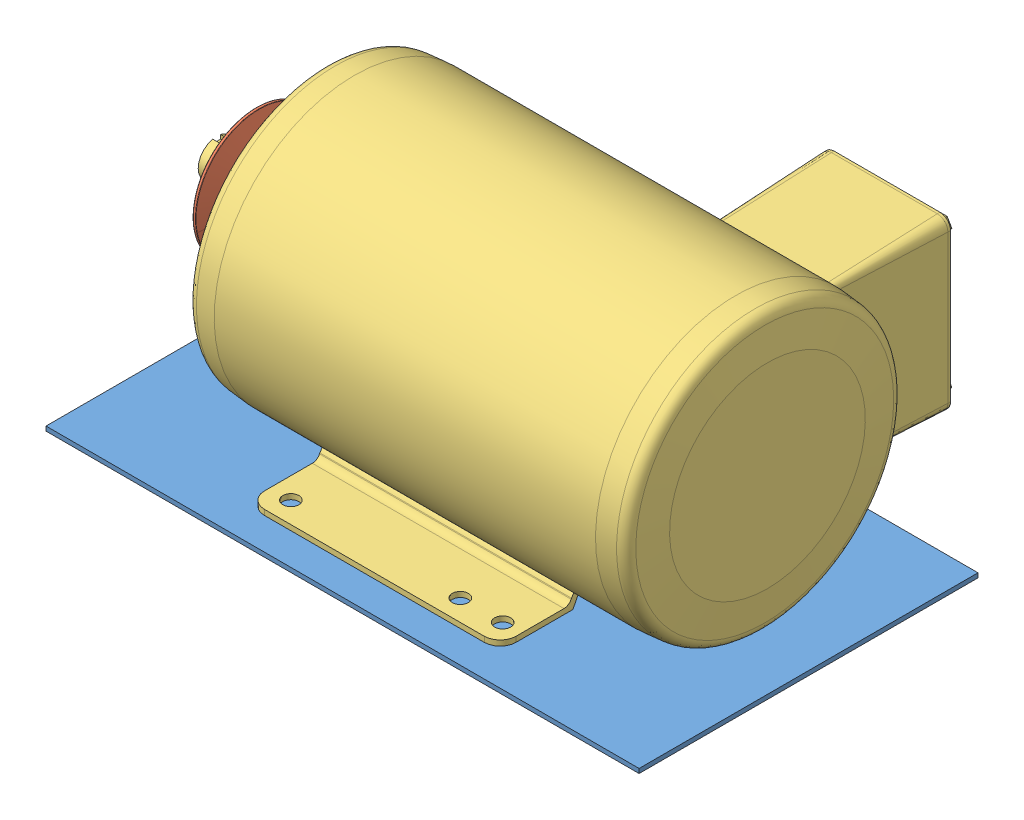
SolidWorks assembly Motor Assembly, configuration Default. Lengths in mm.
Overall size (355.6 175.63 244.09).
3 component instances, 3 part files, 6 mates.
Components (placement in the parent):
- motor stand-1: motor stand [Default] at (-72.8682 166.1231 394.6609) size (355.6 2.66 203.2)
- motor pulley-1: motor pulley [Default] at (-20.5124 224.7511 312.9655) x (0 0.979314 0.202344) z (-1 0 0) size (76.2 76.2 27.17)
- Motor-1: Motor [Default] at (-72.1062 255.0231 293.0609) x (0 0 1) z (-1 0 0) size (226.57 172.97 330.2)
Mates (geometry in assembly coordinates):
- Coincident1: coincident anti-aligned: plane of motor stand-1 through (-72.8682 166.1231 394.6609) normal (0 1 0); plane of Motor-1 through (170.8448 166.1231 366.0859) normal (0 -1 0)
- Parallel1: parallel aligned: line of motor stand-1 through (-72.8682 166.1231 394.6609) axis (1 0 0); line of Motor-1 through (39.0188 169.2981 375.6109) axis (1 0 0)
- Concentric1: concentric anti-aligned: cylinder of motor pulley-1 through (-125.2874 255.0231 293.0609) axis (1 0 0) radius 11.1125; cylinder of Motor-1 through (-72.1062 255.0231 293.0609) axis (-1 0 0) radius 11.1125
- Coincident6: coincident: plane of motor pulley-1 through (-59.4062 255.0231 293.0609) normal (-1 0 0); line of Motor-1 through (-59.4062 266.1356 293.0609) axis (0 -1 0)
- Coincident7: coincident aligned: line of motor stand-1 through (104.9318 166.1231 191.4609) axis (0 0 1); line of Motor-1 through (104.9318 166.1231 210.5109) axis (0 0 1)
- Coincident8: coincident aligned: line of motor stand-1 through (-72.8682 166.1231 293.0609) axis (1 0 0); line of Motor-1 through (30.5695 166.1231 293.0609) axis (1 0 0)
